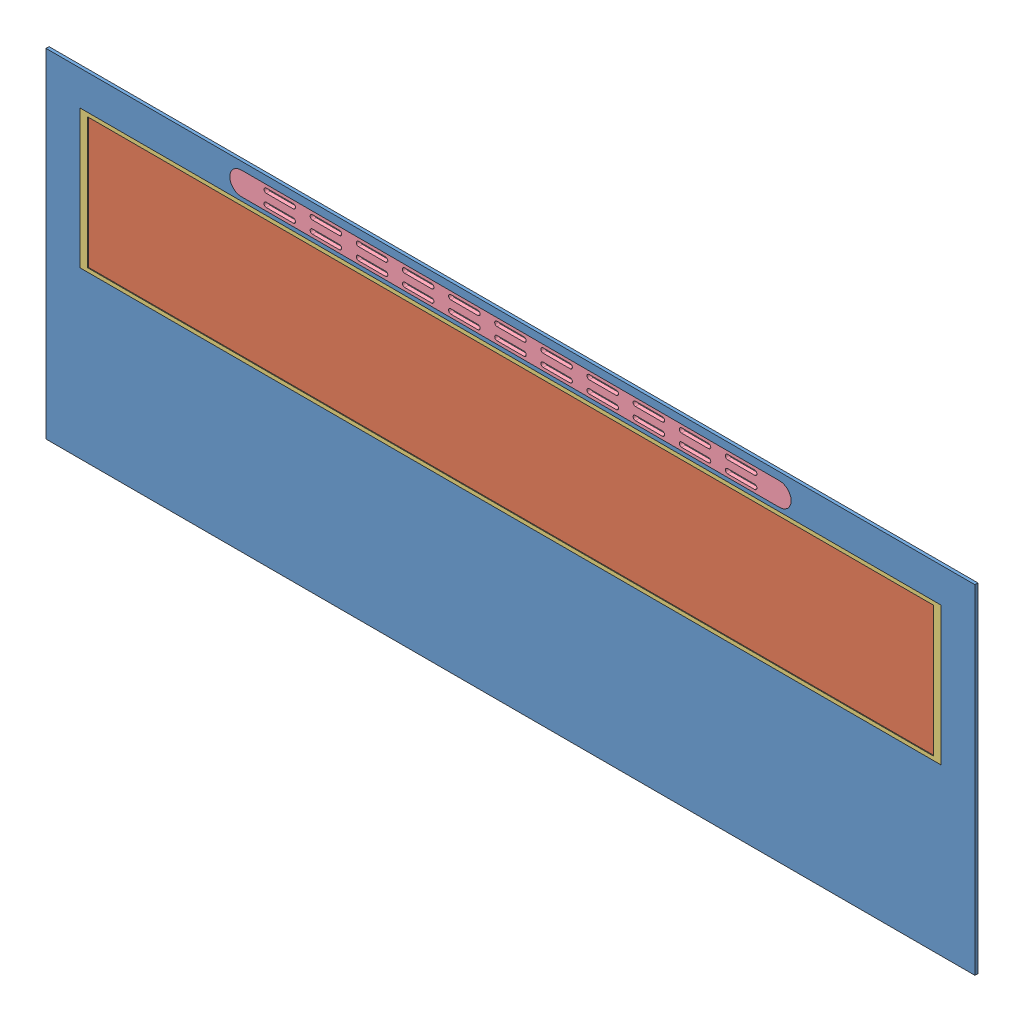
SolidWorks assembly A_PortaModulo, configuration Default. Lengths in mm.
Overall size (1208 440 24).
5 component instances, 5 part files, 7 mates.
Components (placement in the parent):
- Porta_estrutura-1: Porta_estrutura [Default] at (-1043.1108 -124.4662 -601.0303) size (1208 440 4)
- Vidro_porta-1: Vidro_porta [Default] at (-1043.1108 -39.4662 -599.0303) size (1120 180 1)
- Encaixe_moldura_vidro-1: Encaixe_moldura_vidro [Default] at (-1043.1108 -39.4662 -597.0303) x (-1 0 0) z (0 0 -1) size (1120 180 3)
- GrelhaRespiracao-1: GrelhaRespiracao [Default] at (-1043.1108 70.5338 -602.0303) size (736 36 5)
- Puxador_porta_modulo-1: Puxador_porta_modulo [Default] at (-1043.1108 -234.4662 -621.0303) x (-0.416199 0.909274 0) z (0 0 -1) size (15 15 20)
Mates (geometry in assembly coordinates):
- Coincident4: coincident: line of Porta_estrutura-1 through (-483.1108 50.5338 -599.0303) axis (-1 0 0); line of Vidro_porta-1 through (-483.1108 50.5338 -599.0303) axis (-1 0 0)
- Coincident5: coincident: point of Porta_estrutura-1; point of Vidro_porta-1
- Coincident9: coincident: circle of Porta_estrutura-1; circle of Encaixe_moldura_vidro-1
- Coincident10: coincident: circle of Porta_estrutura-1; circle of Encaixe_moldura_vidro-1
- Coincident11: coincident: line of Porta_estrutura-1 through (-1393.1108 85.5338 -601.0303) axis (1 0 0); line of GrelhaRespiracao-1 through (-1393.1108 85.5338 -601.0303) axis (1 0 0)
- Concentric1: concentric: cylinder of Porta_estrutura-1 through (-693.1108 70.5338 -607.0303) axis (0 0 1) radius 15; cylinder of GrelhaRespiracao-1 through (-693.1108 70.5338 -597.0303) axis (0 0 -1) radius 15
- Coincident12: coincident: circle of Puxador_porta_modulo-1; circle of assembly
